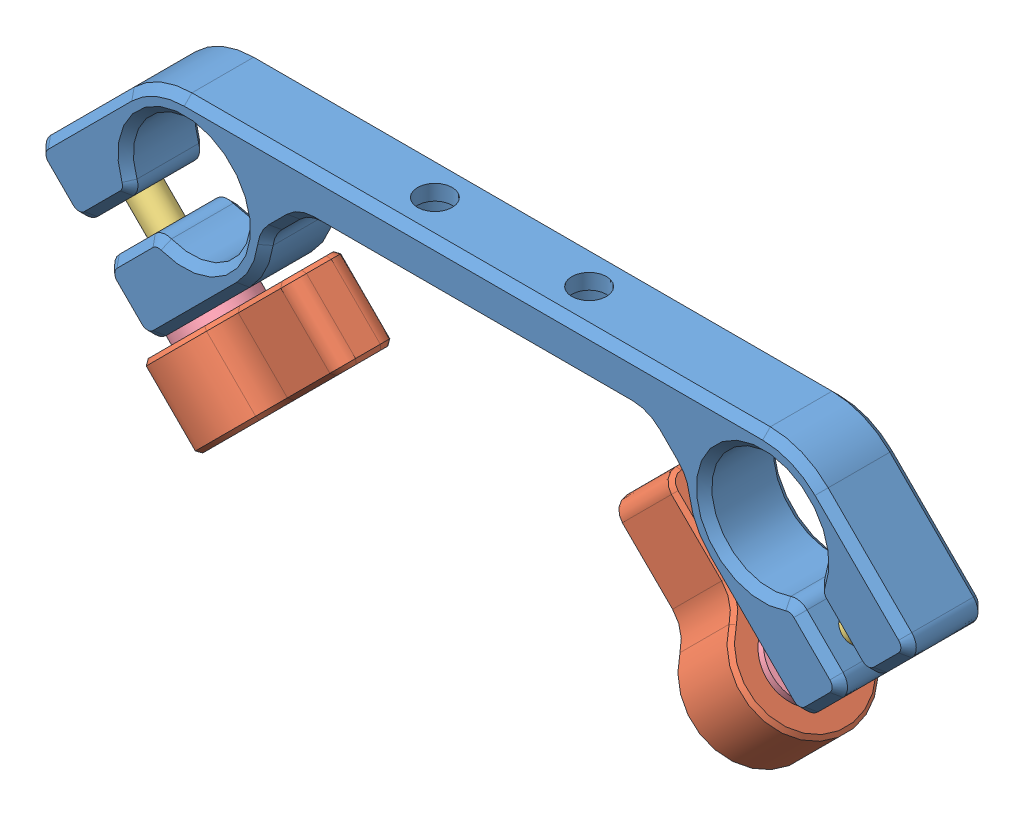
SolidWorks assembly holder_rods_screw, configuration По умолчанию. Lengths in mm.
Overall size (113.29 40.8 18.88).
9 component instances, 4 part files, 4 mates.
Components (placement in the parent):
- holder_rods-1: holder_rods [По умолчанию] at (-44.8957 15.0606 28.9982) size (112.85 29.52 10)
- flag_screw-1: flag_screw [По умолчанию] at (-112.3412 -12.7768 79.6145) x (-0.072364 -0.072364 0.99475) z (0.703394 0.703394 0.102338) size (16 29 29)
  - flag-1: flag [По умолчанию] at (-48.2962 13.0906 23.7085) size (16 10 29)
  - socket head cap screw_din-1: socket head cap screw_din [DIN 912 M4 x 25 --- 25N] at (-48.2962 23.0906 23.7085) x (0 -1 0) z (0 0 1) size (29 7 7)
  - plain washer 6902 type abc_din-1: plain washer 6902 type abc_din [DIN 6902-A4.55] at (-48.2962 13.0906 23.7085) x (0 -1 0) z (-0.000413 0 1) size (1 10 10)
- flag_screw-2: flag_screw [По умолчанию] at (19.0267 -9.2538 -14.3783) x (-0.002403 0.002403 -0.999994) z (-0.707103 0.707103 0.003398) size (16 29 29)
  - flag-1: flag [По умолчанию] at (-48.2962 13.0906 23.7085) size (16 10 29)
  - socket head cap screw_din-1: socket head cap screw_din [DIN 912 M4 x 25 --- 25N] at (-48.2962 23.0906 23.7085) x (0 -1 0) z (0 0 1) size (29 7 7)
  - plain washer 6902 type abc_din-1: plain washer 6902 type abc_din [DIN 6902-A4.55] at (-48.2962 13.0906 23.7085) x (0 -1 0) z (-0.000413 0 1) size (1 10 10)
Mates (geometry in assembly coordinates):
- Совпадение1: coincident anti-aligned: plane of holder_rods-1 through (-74.9004 7.5653 38.9982) normal (0.707107 -0.707107 0); plane of flag_screw-1/plain washer 6902 type abc_din-1 through (-83.6205 -1.1549 33.9982) normal (-0.707107 0.707107 0)
- Концентричный1: concentric aligned: cylinder of holder_rods-1 through (-83.6205 -1.1549 33.9982) axis (0.707107 -0.707107 0) radius 1.65; cylinder of flag_screw-1/socket head cap screw_din-1 through (-53.3917 -31.3837 33.9982) axis (0.707107 -0.707107 0) radius 2
- Совпадение2: coincident anti-aligned: plane of holder_rods-1 through (-14.891 7.5653 38.9982) normal (-0.707107 -0.707107 0); plane of flag_screw-2/plain washer 6902 type abc_din-1 through (-6.1709 -1.1549 33.9982) normal (0.707107 0.707107 0)
- Концентричный2: concentric aligned: cylinder of holder_rods-1 through (-6.1709 -1.1549 33.9982) axis (-0.707107 -0.707107 0) radius 1.65; cylinder of flag_screw-2/socket head cap screw_din-1 through (-36.3997 -31.3837 33.9982) axis (-0.707107 -0.707107 0) radius 2
